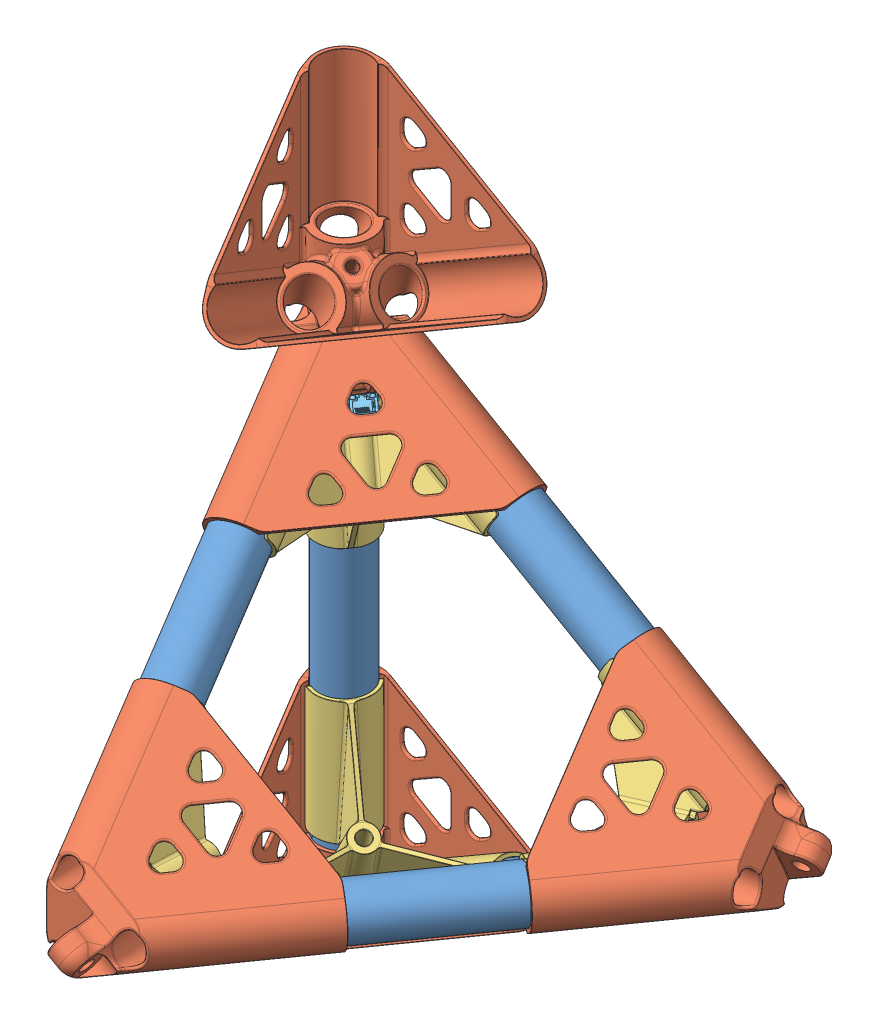
SolidWorks assembly Assembly, configuration Default. Lengths in mm.
Overall size (472 571.74 445).
20 component instances, 5 part files, 34 mates.
Components (placement in the parent):
- Pipe-1: Pipe [Default] at (0 -50.8 0) x (-0.57735 0 0.816497) z (0 1 0) size (38.1 38.1 304.8)
- Pipe-2: Pipe [Default] at (43.9941 -25.4 0) x (0.5 0.866025 0) z (-0.866025 0.5 0) size (38.1 38.1 304.8)
- Pipe-3: Pipe [Default] at (14.6647 -25.4 41.478) x (0.944444 0.288675 -0.157135) z (-0.288675 0.5 -0.816497) size (38.1 38.1 304.8)
- Corner Outer-1: Corner Outer [Default] x (0.816497 0 0.57735) z (-0.57735 0 0.816497) size (146.72 165.34 190.05)
- Corner Outer-2: Corner Outer [Default] x (0.816497 0 0.57735) z (0.57735 0 -0.816497) size (146.72 165.34 190.05)
- Inner Corner Assembly^Assembly-1: Inner Corner Assembly^Assembly [Default] x (0.816497 0 0.57735) z (-0.57735 0 0.816497) size (121.32 132.99 170.18) (virtual)
  - Corner Inner-1: Corner Inner [Default] at origin size (121.32 132.99 170.18)
  - LEDsPCB^Inner Corner Assembly_Assembly-1: LEDsPCB^Inner Corner Assembly_Assembly [Default] at (39.2606 -55.5229 0) x (0 0 -1) z (0.816497 0.57735 0) size (91.37 1.61 79.9) (virtual)
  - RJ45.ipt-1: RJ45.ipt [Default] at (64.4043 -27.4 0) x (0 0 1) z (0.816497 0.57735 0) size (17.91 14.48 20.57)
  - RJ45.ipt-2: RJ45.ipt [Default] at (19.3748 -59.2407 31.8407) x (-0.707107 -0.5 -0.5) z (-0.408248 -0.288675 0.866025) size (17.91 14.48 20.57)
  - RJ45.ipt-3: RJ45.ipt [Default] at (19.3748 -59.2407 -31.8407) x (0.707107 0.5 -0.5) z (-0.408248 -0.288675 -0.866025) size (17.91 14.48 20.57)
- Corner Outer-3: Corner Outer [Default] at (0 -406.4 0) x (0.816497 0 0.57735) z (0.57735 0 -0.816497) size (146.72 165.34 190.05)
- Corner Inner-1: Corner Inner [Default] at (0 -406.4 0) x (0.816497 0 0.57735) z (0.57735 0 -0.816497) size (121.32 132.99 170.18)
- Corner Outer-5: Corner Outer [Default] at (351.9527 -203.2 0) x (-0.408248 0.707107 0.57735) z (-0.288675 0.5 -0.816497) size (146.72 165.34 190.05)
- Corner Inner-2: Corner Inner [Default] at (351.9527 -203.2 0) x (-0.408248 0.707107 0.57735) z (-0.288675 0.5 -0.816497) size (121.32 132.99 170.18)
- Corner Outer-6: Corner Outer [Default] at (117.3176 -203.2 331.8242) x (0.408248 0.707107 -0.57735) z (0.866025 -0.5 0) size (146.72 165.34 190.05)
- Corner Inner-3: Corner Inner [Default] at (117.3176 -203.2 331.8242) x (0.408248 0.707107 -0.57735) z (0.866025 -0.5 0) size (121.32 132.99 170.18)
- Pipe-4: Pipe [Default] at (102.6529 -228.6 290.3462) x (0.866025 -0.5 0) z (0.288675 0.5 0.816497) size (38.1 38.1 304.8)
- Pipe-5: Pipe [Default] at (307.9586 -228.6 0) x (-0.288675 0.5 -0.816497) z (0.866025 0.5 0) size (38.1 38.1 304.8)
- Pipe-6: Pipe [Default] at (146.647 -203.2 290.3462) x (0 1 0) z (-0.57735 0 0.816497) size (38.1 38.1 304.8)
Mates (geometry in assembly coordinates):
- Concentric1: concentric anti-aligned: cylinder of Pipe-1 through (0 -409.4815 0) axis (0 1 0) radius 19.05; line of assembly
- Coincident2: coincident: plane of Pipe-1 through (0 -50.8 0) normal (0 1 0); point of assembly
- Concentric2: concentric anti-aligned: cylinder of Pipe-2 through (354.6214 -204.7408 0) axis (-0.866025 0.5 0) radius 19.05; line of assembly
- Coincident5: coincident: plane of Pipe-2 through (43.9941 -25.4 0) normal (-0.866025 0.5 0); point of assembly
- Concentric3: concentric anti-aligned: cylinder of Pipe-3 through (118.2071 -204.7408 334.3403) axis (-0.288675 0.5 -0.816497) radius 19.05; line of assembly
- Coincident7: coincident: plane of Pipe-3 through (14.6647 -25.4 41.478) normal (-0.288675 0.5 -0.816497); point of assembly
- Coincident8: coincident: unknown of ?
- Parallel2: parallel aligned: plane of Pipe-1 through (0 -50.8 0) normal (0 1 0); plane of Corner Outer-1
- Parallel3: parallel: plane of ? through (0 0 0) normal (0.816497 0 0.57735)
- Coincident11: coincident: point of Corner Outer-2; point of assembly
- Coincident12: coincident anti-aligned: plane of Corner Outer-2; plane of assembly through (0 0 0) normal (0 1 0)
- Parallel6: parallel: plane of Corner Outer-2; line of assembly
- Coincident16: coincident: plane of Pipe-1; line of Corner Outer-1 through (0 0 0) axis (0.471405 -0.816497 0.333333)
- Coincident17: coincident aligned: plane of Corner Outer-1 through (0 0 0) normal (-0.57735 0 0.816497); plane of Inner Corner Assembly^Assembly-1/Corner Inner-1 through (0 0 0) normal (-0.57735 0 0.816497)
- Coincident18: coincident aligned: plane of Corner Outer-1; plane of Inner Corner Assembly^Assembly-1/Corner Inner-1
- Coincident19: coincident aligned: plane of Corner Outer-1 through (0 0 0) normal (0.816497 0 0.57735); plane of Inner Corner Assembly^Assembly-1/Corner Inner-1 through (0 0 0) normal (0.816497 0 0.57735)
- Coincident20: coordinate: point of Corner Outer-3; point of Corner Inner-1
- Coincident21: coordinate: point of Corner Outer-5; point of Corner Inner-2
- Coincident22: coordinate: point of Corner Outer-6; point of Corner Inner-3
- Concentric4: concentric anti-aligned: cylinder of ? through (0 -396.4424 0) axis (0 -1 0) radius 21.844
- Concentric5: concentric anti-aligned: cylinder of ? through (8.6235 -401.4212 0) axis (-0.866025 -0.5 0) radius 21.844
- Concentric6: concentric anti-aligned: cylinder of ? through (114.4431 -208.1788 323.6939) axis (0.288675 0.5 0.816497) radius 21.844
- Concentric7: concentric aligned: cylinder of ? through (343.3292 -208.1788 0) axis (0.866025 0.5 0) radius 21.844
- Concentric8: concentric aligned: cylinder of ? through (343.3292 -198.2212 0) axis (0.866025 -0.5 0) radius 21.844
- Concentric9: concentric aligned: cylinder of ? through (114.4431 -198.2212 323.6939) axis (0.288675 -0.5 0.816497) radius 21.844
- Concentric10: concentric anti-aligned: cylinder of Corner Inner-1 through (57.8652 -306.1746 163.6675) axis (-0.288675 -0.5 -0.816497) radius 19.05; cylinder of Pipe-4 through (-0.8896 -407.9408 -2.5161) axis (0.288675 0.5 0.816497) radius 19.05
- Concentric11: concentric aligned: cylinder of Corner Outer-5 through (219.9705 -279.4 0) axis (0.866025 0.5 0) radius 19.05; cylinder of Pipe-5 through (-2.6687 -407.9408 0) axis (0.866025 0.5 0) radius 19.05
- Concentric12: concentric anti-aligned: cylinder of Corner Outer-5 through (263.9645 -203.2 124.4341) axis (0.57735 0 -0.816497) radius 19.05; cylinder of Pipe-6 through (353.7319 -203.2 -2.5161) axis (-0.57735 0 0.816497) radius 19.05
- Coincident29: coincident anti-aligned: plane of Corner Outer-3 through (43.9941 -381 0) normal (0.866025 0.5 0); plane of Pipe-5 through (43.9941 -381 0) normal (-0.866025 -0.5 0)
- Coincident30: coincident anti-aligned: plane of Corner Outer-3 through (14.6647 -381 41.478) normal (0.288675 0.5 0.816497); plane of Pipe-4 through (14.6647 -381 41.478) normal (-0.288675 -0.5 -0.816497)
- Coincident31: coincident anti-aligned: plane of Corner Outer-5 through (322.6233 -203.2 41.478) normal (-0.57735 0 0.816497); plane of Pipe-6 through (322.6233 -203.2 41.478) normal (0.57735 0 -0.816497)
- Coincident33: coincident aligned: plane of Corner Inner-3 through (117.3176 -203.2 331.8242) normal (0.866025 -0.5 0); plane of Pipe-4
- Coincident34: coincident aligned: plane of Corner Inner-2 through (351.9527 -203.2 0) normal (-0.288675 0.5 -0.816497); plane of Pipe-5
- Coincident35: coincident: point of Corner Inner-3; plane of Pipe-6
